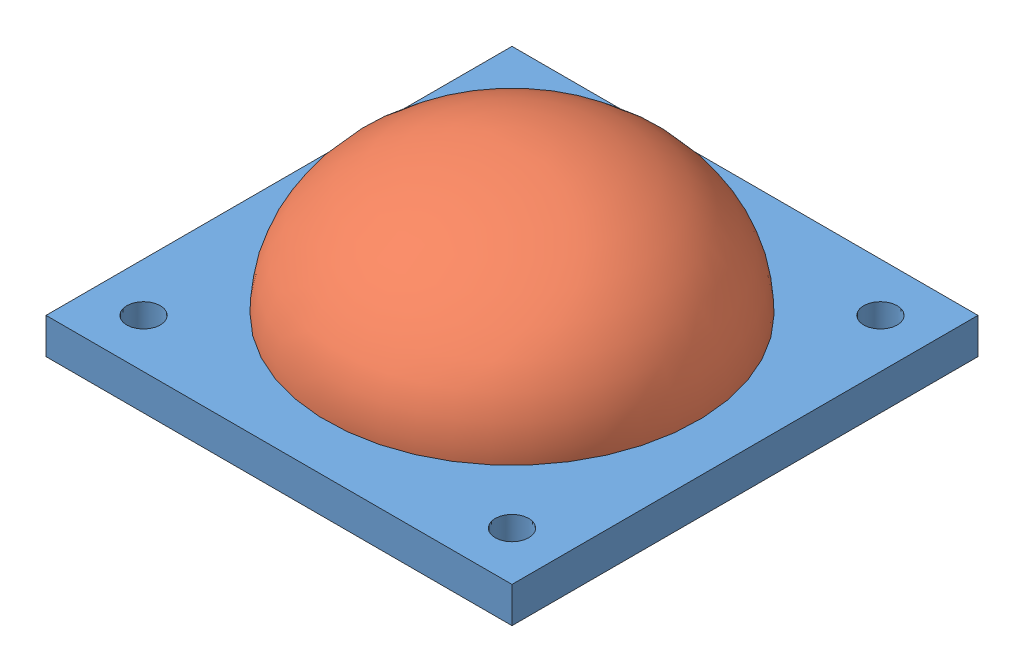
SolidWorks assembly ldr-33, configuration Default. Lengths in mm.
Overall size (47.86 16.7 47.86).
2 component instances, 2 part files, 1 mates.
Components (placement in the parent):
- osnova-1: osnova [Default] at (33.659 17.6063 17.9646) x (0 0 1) z (0 -1 0) size (43 43 3.3)
- kupol-v2-1: kupol-v2 [Default] at (-7.5796 23.7577 65.9105) x (0.801391 0 0.598141) z (-0.598141 0 0.801391) size (34.2 13.3 34.2)
Mates (geometry in assembly coordinates):
- Lock1: lock: unknown of osnova-1; unknown of kupol-v2-1
